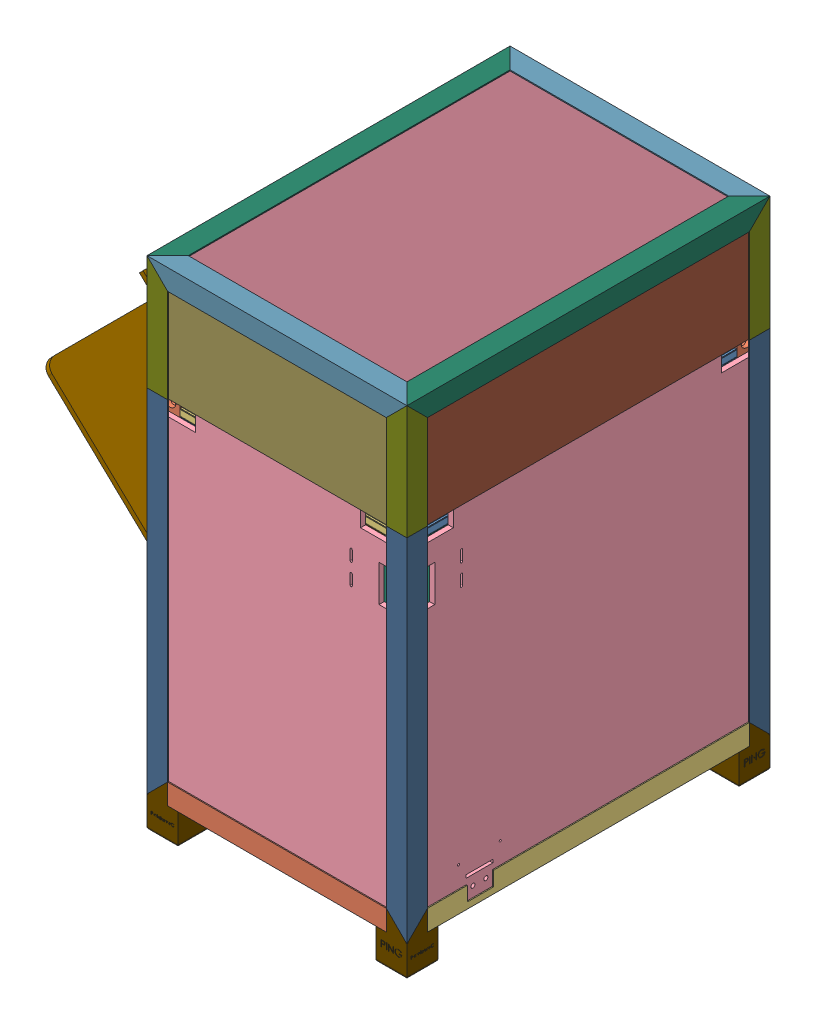
SolidWorks assembly carcasse, configuration Défaut. Lengths in mm.
Overall size (850.58 964 704).
62 component instances, 25 part files, 73 mates.
Components (placement in the parent):
- cadre-1: cadre [Défaut] at (-215.194 -19.8636 -400) size (480 40 680)
  - prof_40x40x600mm-1: prof_40x40x600mm [Défaut] at (-14.8937 4.0689 600) size (40 40 600)
  - Rexroth-Default-1: Rexroth-Default [Default] at (-14.8937 24.0689 720) x (0 -1 0) z (-1 0 0) size (40 40 40)
  - prof_40x40x600mm-3: prof_40x40x600mm [Défaut] at (425.1063 4.0689 600) size (40 40 600)
  - Rexroth-Default-3: Rexroth-Default [Default] at (-14.8937 24.0689 80) x (0 -1 0) z (0 0 -1) size (40 40 40)
  - Rexroth-Default-4: Rexroth-Default [Default] at (425.1063 24.0689 80) x (0 -1 0) z (1 0 0) size (40 40 40)
  - Rexroth-Default-5: Rexroth-Default [Default] at (425.1063 24.0689 720) x (0 -1 0) z (0 0 1) size (40 40 40)
  - prof_40x40x300mm-1: prof_40x40x300mm [Défaut] at (105.1063 4.0689 720) x (0 0 1) z (-1 0 0) size (40 40 400)
  - prof_40x40x300mm-2: prof_40x40x300mm [Défaut] at (105.1063 4.0689 80) x (0 0 1) z (-1 0 0) size (40 40 400)
- prof_40x40x600mm-1: prof_40x40x600mm [Défaut] at (209.9123 104.2053 -320) x (1 0 0) z (0 -1 0) size (40 40 600)
- prof_40x40x600mm-2: prof_40x40x600mm [Défaut] at (209.9123 104.2053 320) x (1 0 0) z (0 -1 0) size (40 40 600)
- prof_40x40x600mm-3: prof_40x40x600mm [Défaut] at (-230.0877 104.2053 320) x (1 0 0) z (0 -1 0) size (40 40 600)
- prof_40x40x600mm-4: prof_40x40x600mm [Défaut] at (-230.0877 104.2053 -320) x (1 0 0) z (0 -1 0) size (40 40 600)
- cadre-2: cadre [Défaut] at (195.0186 628.2742 -400) x (-1 0 0) z (0 0 1) size (480 40 680)
  - prof_40x40x600mm-1: prof_40x40x600mm [Défaut] at (-14.8937 4.0689 600) size (40 40 600)
  - Rexroth-Default-1: Rexroth-Default [Default] at (-14.8937 24.0689 720) x (0 -1 0) z (-1 0 0) size (40 40 40)
  - prof_40x40x600mm-3: prof_40x40x600mm [Défaut] at (425.1063 4.0689 600) size (40 40 600)
  - Rexroth-Default-3: Rexroth-Default [Default] at (-14.8937 24.0689 80) x (0 -1 0) z (0 0 -1) size (40 40 40)
  - Rexroth-Default-4: Rexroth-Default [Default] at (425.1063 24.0689 80) x (0 -1 0) z (1 0 0) size (40 40 40)
  - Rexroth-Default-5: Rexroth-Default [Default] at (425.1063 24.0689 720) x (0 -1 0) z (0 0 1) size (40 40 40)
  - prof_40x40x300mm-1: prof_40x40x300mm [Défaut] at (105.1063 4.0689 720) x (0 0 1) z (-1 0 0) size (40 40 400)
  - prof_40x40x300mm-2: prof_40x40x300mm [Défaut] at (105.1063 4.0689 80) x (0 0 1) z (-1 0 0) size (40 40 400)
- plaque_acrylique_680x670-2: plaque_acrylique_680x670 [Défaut] at (229.9123 299.2053 0) x (0 0 -1) z (1 0 0) size (680 670 10)
- plaque_acrylique_380x670_G-1: plaque_acrylique_380x670_G [Défaut] at (39.9123 299.2053 -350) size (480 670 10)
- plaque_acrylique_680x670_porte-1: plaque_acrylique_680x670_porte [Défaut] at (-260.0877 299.2053 0) x (0 0 -1) z (1 0 0) size (680 670 10)
- charniere-1: charniere [Défaut] at (-253.7309 154.2053 256.2875) x (0 0 1) z (0 -1 0) size (40 29.08 53.23)
  - axe charnière-1: axe charnière [Défaut] at (-76.2875 9.8568 0) size (40 5 5)
  - batant charnière-1: batant charnière [Défaut] at (-76.2875 10.1991 -17.6196) size (40 7 33.5)
  - batant charnière-2: batant charnière [Défaut] at (-36.2875 -2.6626 12.4029) x (-1 0 0) z (0 0.723942 -0.689861) size (40 7 33.5)
- charniere-2: charniere [Défaut] at (-253.7309 154.2053 -143.7125) x (0 0 1) z (0 -1 0) size (40 29.08 53.23)
  - axe charnière-1: axe charnière [Défaut] at (-76.2875 9.8568 0) size (40 5 5)
  - batant charnière-1: batant charnière [Défaut] at (-76.2875 10.1991 -17.6196) size (40 7 33.5)
  - batant charnière-2: batant charnière [Défaut] at (-36.2875 -2.6626 12.4029) x (-1 0 0) z (0 0.723942 -0.689861) size (40 7 33.5)
- porte-1: porte [Défaut] at (-366.1448 256.769 0) x (0 0 -1) z (0.689861 0.723942 0) size (480 480 10)
- eclisse_40x40x670_bisote_x1-1: eclisse_40x40x670_bisote_x1 [Défaut] at (-242.0877 -47.7947 -331.8864) size (40 682 40)
- eclisse_40x40x670_bisote_x1-2: eclisse_40x40x670_bisote_x1 [Défaut] at (-241.9741 -47.7947 332) x (0 0 -1) z (1 0 0) size (40 682 40)
- eclisse_40x40x670_bisote_x1-3: eclisse_40x40x670_bisote_x1 [Défaut] at (221.9123 -47.7947 331.8864) x (-1 0 0) z (0 0 -1) size (40 682 40)
- eclisse_40x40x670_bisote_x1-4: eclisse_40x40x670_bisote_x1 [Défaut] at (221.7986 -47.7947 -332) x (0 0 1) z (-1 0 0) size (40 682 40)
- couvercle-1: couvercle [Défaut] at (227.4119 747.9268 345) size (504 222 704)
  - plaque_acrylique_680x210-2: plaque_acrylique_680x210 [Défaut] at (-487.4996 -8.7215 -345) x (0 0 -1) z (1 0 0) size (680 210 10)
  - plaque_acrylique_380x210-2: plaque_acrylique_380x210 [Défaut] at (-187.4996 -8.7215 -695) size (480 210 10)
  - plaque_acrylique_380x680-1: plaque_acrylique_380x680 [Défaut] at (-187.4996 96.2785 -345) x (1 0 0) z (0 1 0) size (480 680 10)
  - eclisse_40x40x404_bisote_x2-1: eclisse_40x40x404_bisote_x2 [Défaut] at (14.5004 88.1649 -677) x (0 0 1) z (0 -1 0) size (40 504 40)
  - eclisse_40x40x704_bisote_x2-1: eclisse_40x40x704_bisote_x2 [Défaut] at (-5.6132 88.2785 -697) x (0 -1 0) z (-1 0 0) size (40 704 40)
  - eclisse_40x40x404_bisote_x2-2: eclisse_40x40x404_bisote_x2 [Défaut] at (-489.4996 88.1649 -13) x (0 0 -1) z (0 -1 0) size (40 504 40)
  - eclisse_40x40x704_bisote_x2-2: eclisse_40x40x704_bisote_x2 [Défaut] at (-469.4996 88.1649 -697) x (1 0 0) z (0 -1 0) size (40 704 40)
  - eclisse_40x40x222_bisote_x1-1: eclisse_40x40x222_bisote_x1 [Défaut] at (-469.386 108.2785 -677) x (0 0 1) z (1 0 0) size (40 222 40)
  - eclisse_40x40x222_bisote_x1-2: eclisse_40x40x222_bisote_x1 [Défaut] at (-5.4996 108.2785 -676.8864) x (-1 0 0) z (0 0 1) size (40 222 40)
  - eclisse_40x40x222_bisote_x1-4: eclisse_40x40x222_bisote_x1 [Défaut] at (-469.4996 108.2785 -13.1136) x (1 0 0) z (0 0 -1) size (40 222 40)
  - plaque_acrylique_380x210_Moteur-1: plaque_acrylique_380x210_Moteur [Défaut] at (-187.4996 -8.7215 -5) size (480 210 10)
  - plaque_acrylique_680x210_moteur-1: plaque_acrylique_680x210_moteur [Défaut] at (2.5004 -8.7215 -345) x (0 0 -1) z (1 0 0) size (680 210 10)
  - eclisse_40x40x222_bisote_x1_Moteur-1: eclisse_40x40x222_bisote_x1_Moteur [Défaut] at (-5.6132 108.2785 -13) x (0 0 -1) z (-1 0 0) size (40 222 40)
- plaque_acrylique_bas_380x680-1: plaque_acrylique_bas_380x680 [Défaut] at (39.9123 -35.7947 0) x (1 0 0) z (0 -1 0) size (480 680 10)
- Pied-1: Pied [Défaut] at (181.9123 -47.7947 -292) x (-1 0 0) z (0 -1 0) size (60 60 100)
- Pied-2: Pied [Défaut] at (181.9123 -47.7947 292) x (0 0 -1) z (0 -1 0) size (60 60 100)
- Pied-3: Pied [Défaut] at (-202.0877 -47.7947 292) x (1 0 0) z (0 -1 0) size (60 60 100)
- Pied-4: Pied [Défaut] at (-202.0877 -47.7947 -292) x (0 0 1) z (0 -1 0) size (60 60 100)
- eclisse_bas_40x40x704-2: eclisse_bas_40x40x704 [Défaut] at (-242.0877 -27.681 312) x (1 0 0) z (0 1 0) size (40 624 40)
- eclisse_bas_40x40x404-1: eclisse_bas_40x40x404 [Défaut] at (-222.0877 -27.681 -332) x (0 0 1) z (0 1 0) size (40 424 40)
- eclisse_bas_40x40x404-2: eclisse_bas_40x40x404 [Défaut] at (201.9123 -27.681 332) x (0 0 -1) z (0 1 0) size (40 424 40)
- eclisse_bas_support_Z_40x40x704-1: eclisse_bas_support_Z_40x40x704 [Défaut] at (221.7986 -27.7947 312) x (0 1 0) z (-1 0 0) size (40 624 40)
- plaque_acrylique_380x670_D-2: plaque_acrylique_380x670_D [Défaut] at (-60.0877 299.2053 350) x (-1 0 0) z (0 0 -1) size (480 670 10)
Mates (geometry in assembly coordinates):
- Coïncidente1: coincident anti-aligned: plane of cadre-1/Rexroth-Default-3 through (-230.0877 4.2053 -320) normal (0 1 0); plane of prof_40x40x600mm-4 through (-213.0877 4.2053 -337) normal (0 -1 0)
- Coïncidente2: coincident anti-aligned: plane of cadre-1/Rexroth-Default-1 through (-230.0877 4.2053 320) normal (0 1 0); plane of prof_40x40x600mm-3 through (-213.0877 4.2053 303) normal (0 -1 0)
- Coïncidente3: coincident anti-aligned: plane of cadre-1/Rexroth-Default-5 through (209.9123 4.2053 320) normal (0 1 0); plane of prof_40x40x600mm-2 through (226.9123 4.2053 303) normal (0 -1 0)
- Coïncidente4: coincident anti-aligned: plane of cadre-1/Rexroth-Default-4 through (209.9123 4.2053 -320) normal (0 1 0); plane of prof_40x40x600mm-1 through (226.9123 4.2053 -337) normal (0 -1 0)
- Coïncidente5: coincident aligned: plane of cadre-1/Rexroth-Default-4 through (229.9123 -15.7947 -320) normal (1 0 0); plane of prof_40x40x600mm-1 through (229.9123 604.2053 -314) normal (1 0 0)
- Coïncidente6: coincident aligned: plane of cadre-1/Rexroth-Default-4 through (209.9123 -15.7947 -340) normal (0 0 -1); plane of prof_40x40x600mm-1 through (215.9123 604.2053 -340) normal (0 0 -1)
- Coïncidente7: coincident aligned: plane of cadre-1/Rexroth-Default-5 through (229.9123 -15.7947 320) normal (1 0 0); plane of prof_40x40x600mm-2 through (229.9123 604.2053 303) normal (1 0 0)
- Coïncidente8: coincident aligned: plane of cadre-1/Rexroth-Default-5 through (209.9123 -15.7947 340) normal (0 0 1); plane of prof_40x40x600mm-2 through (226.9123 604.2053 340) normal (0 0 1)
- Coïncidente9: coincident aligned: plane of cadre-1/Rexroth-Default-1 through (-230.0877 -15.7947 340) normal (0 0 1); plane of prof_40x40x600mm-3 through (-213.0877 604.2053 340) normal (0 0 1)
- Coïncidente10: coincident aligned: plane of cadre-1/Rexroth-Default-1 through (-250.0877 -15.7947 320) normal (-1 0 0); plane of prof_40x40x600mm-3 through (-250.0877 604.2053 337) normal (-1 0 0)
- Coïncidente11: coincident aligned: plane of cadre-1/Rexroth-Default-3 through (-250.0877 -15.7947 -320) normal (-1 0 0); plane of prof_40x40x600mm-4 through (-250.0877 604.2053 -303) normal (-1 0 0)
- Coïncidente12: coincident aligned: plane of cadre-1/Rexroth-Default-3 through (-230.0877 -15.7947 -340) normal (0 0 -1); plane of prof_40x40x600mm-4 through (-247.0877 604.2053 -340) normal (0 0 -1)
- Coïncidente13: coincident anti-aligned: plane of prof_40x40x600mm-1 through (226.9123 604.2053 -337) normal (0 1 0); plane of cadre-2/Rexroth-Default-3 through (209.9123 604.2053 -320) normal (0 -1 0)
- Coïncidente14: coincident aligned: plane of prof_40x40x600mm-3 through (-250.0877 604.2053 337) normal (-1 0 0); plane of cadre-2/Rexroth-Default-5 through (-250.0877 624.2053 320) normal (-1 0 0)
- Coïncidente15: coincident aligned: plane of prof_40x40x600mm-3 through (-236.0877 604.2053 340) normal (0 0 1); plane of cadre-2/Rexroth-Default-5 through (-230.0877 624.2053 340) normal (0 0 1)
- Coïncidente38: coincident anti-aligned: plane of cadre-2/prof_40x40x600mm-1 through (229.9123 630.2053 -300) normal (1 0 0); plane of plaque_acrylique_680x670-2 through (229.9123 299.2053 0) normal (-1 0 0)
- Coïncidente39: coincident aligned: plane of prof_40x40x600mm-2 through (226.9123 604.2053 340) normal (0 0 1); plane of plaque_acrylique_680x670-2 through (239.9123 634.2053 340) normal (0 0 1)
- Coïncidente40: coincident aligned: plane of cadre-1/prof_40x40x600mm-3 through (215.9123 -35.7947 -300) normal (0 -1 0); plane of plaque_acrylique_680x670-2 through (239.9123 -35.7947 340) normal (0 -1 0)
- Coïncidente44: coincident aligned: plane of cadre-1/prof_40x40x300mm-2 through (189.9123 -35.7947 -337) normal (0 -1 0); plane of plaque_acrylique_380x670_G-1 through (-250.0877 -35.7947 -340) normal (0 -1 0)
- Coïncidente45: coincident aligned: plane of cadre-2/Rexroth-Default-4 through (-250.0877 624.2053 -320) normal (-1 0 0); plane of plaque_acrylique_380x670_G-1 through (-250.0877 634.2053 -340) normal (-1 0 0)
- Coïncidente46: coincident anti-aligned: plane of prof_40x40x600mm-4 through (-247.0877 604.2053 -340) normal (0 0 -1); plane of plaque_acrylique_380x670_G-1 through (39.9123 299.2053 -340) normal (0 0 1)
- Coïncidente48: coincident aligned: plane of cadre-2/Rexroth-Default-5 through (-230.0877 624.2053 340) normal (0 0 1); plane of plaque_acrylique_680x670_porte-1 through (-250.0877 634.2053 340) normal (0 0 1)
- Coïncidente50: coincident anti-aligned: plane of plaque_acrylique_680x670_porte-1 through (-260.0877 299.2053 0) normal (-1 0 0); plane of charniere-1/batant charnière-1 through (-260.0877 114.2053 220) normal (1 0 0)
- Coïncidente51: coincident anti-aligned: plane of plaque_acrylique_680x670_porte-1 through (-260.0877 299.2053 0) normal (-1 0 0); plane of charniere-2/batant charnière-1 through (-260.0877 114.2053 -180) normal (1 0 0)
- Distance4: distance = 20 mm anti-aligned: plane of charniere-2/batant charnière-1 through (-263.5877 154.2053 -220) normal (0 0 -1); plane of plaque_acrylique_680x670_porte-1 through (-260.0877 574.2053 -240) normal (0 0 1)
- Coïncidente54: coincident aligned: line of plaque_acrylique_680x670_porte-1 through (-260.0877 154.2053 220) axis (0 0 -1); line of charniere-2/batant charnière-1 through (-260.0877 154.2053 -180) axis (0 0 -1)
- Distance5: distance = 20 mm anti-aligned: plane of plaque_acrylique_680x670_porte-1 through (-260.0877 574.2053 240) normal (0 0 -1); plane of charniere-1/batant charnière-1 through (-263.5877 154.2053 220) normal (0 0 1)
- Coïncidente57: coincident aligned: line of plaque_acrylique_680x670_porte-1 through (-260.0877 154.2053 220) axis (0 0 -1); line of charniere-1/batant charnière-1 through (-260.0877 154.2053 220) axis (0 0 -1)
- Coïncidente62: coincident anti-aligned: plane of charniere-1/batant charnière-2 through (-290.1309 184.3336 180) normal (0.689861 0.723942 0); plane of porte-1 through (-586.947 467.1766 30) normal (-0.689861 -0.723942 0)
- Coïncidente63: coincident anti-aligned: line of charniere-1/batant charnière-2 through (-261.1732 156.7391 200) axis (0 0 1); line of porte-1 through (-261.1732 156.7391 220) axis (0 0 -1)
- Coïncidente64: coincident anti-aligned: plane of plaque_acrylique_680x670_porte-1 through (-260.0877 574.2053 240) normal (0 0 -1); plane of porte-1 through (-558.3301 453.7202 240) normal (0 0 1)
- Coïncidente65: coincident anti-aligned: plane of plaque_acrylique_380x670_G-1 through (39.9123 299.2053 -350) normal (0 0 -1); plane of eclisse_40x40x670_bisote_x1-1 through (-260.0877 634.2053 -350) normal (0 0 1)
- Coïncidente66: coincident anti-aligned: plane of plaque_acrylique_680x670_porte-1 through (-260.0877 299.2053 0) normal (-1 0 0); plane of eclisse_40x40x670_bisote_x1-1 through (-260.0877 634.2053 -350) normal (1 0 0)
- Coïncidente67: coincident aligned: plane of plaque_acrylique_680x670_porte-1 through (-250.0877 634.2053 340) normal (0 1 0); plane of eclisse_40x40x670_bisote_x1-1 through (-242.0877 634.2053 -331.8864) normal (0 1 0)
- Coïncidente68: coincident anti-aligned: plane of plaque_acrylique_680x670-2 through (239.9123 299.2053 0) normal (1 0 0); plane of eclisse_40x40x670_bisote_x1-4 through (239.9123 634.2053 -350) normal (-1 0 0)
- Coïncidente69: coincident anti-aligned: plane of plaque_acrylique_380x670_G-1 through (39.9123 299.2053 -350) normal (0 0 -1); plane of eclisse_40x40x670_bisote_x1-4 through (239.9123 634.2053 -350) normal (0 0 1)
- Coïncidente70: coincident aligned: plane of plaque_acrylique_380x670_G-1 through (-250.0877 634.2053 -340) normal (0 1 0); plane of eclisse_40x40x670_bisote_x1-4 through (221.7986 634.2053 -332) normal (0 1 0)
- Coïncidente72: coincident anti-aligned: plane of plaque_acrylique_680x670_porte-1 through (-260.0877 299.2053 0) normal (-1 0 0); plane of eclisse_40x40x670_bisote_x1-2 through (-260.0877 634.2053 350) normal (1 0 0)
- Coïncidente74: coincident anti-aligned: plane of plaque_acrylique_680x670-2 through (239.9123 299.2053 0) normal (1 0 0); plane of eclisse_40x40x670_bisote_x1-3 through (239.9123 634.2053 350) normal (-1 0 0)
- Coïncidente100: coincident: plane of plaque_acrylique_680x670_porte-1 through (-250.0877 634.2053 340) normal (0 1 0); line of eclisse_40x40x670_bisote_x1-2 through (-260.0877 634.2053 350) axis (0 0 -1)
- Coïncidente101: coincident anti-aligned: plane of prof_40x40x600mm-4 through (-250.0877 604.2053 -326) normal (-1 0 0); plane of plaque_acrylique_680x670_porte-1 through (-250.0877 299.2053 0) normal (1 0 0)
- Coïncidente116: coincident anti-aligned: line of plaque_acrylique_680x670-2 through (239.9123 634.2053 -260) axis (0 0 1); line of couvercle-1/plaque_acrylique_680x210_moteur-1 through (239.9123 634.2053 340) axis (0 0 -1)
- Coïncidente117: coincident anti-aligned: line of plaque_acrylique_380x670_G-1 through (149.9123 634.2053 -350) axis (-1 0 0); line of couvercle-1/plaque_acrylique_380x210-2 through (-170.0877 634.2053 -350) axis (1 0 0)
- Coïncidente118: coincident anti-aligned: plane of cadre-1/prof_40x40x600mm-1 through (-247.0877 -35.7947 -300) normal (0 -1 0); plane of plaque_acrylique_bas_380x680-1 through (39.9123 -35.7947 0) normal (0 1 0)
- Coïncidente119: coincident: plane of cadre-1/prof_40x40x600mm-1 through (-250.0877 -21.7947 -300) normal (-1 0 0); line of plaque_acrylique_bas_380x680-1 through (-250.0877 -35.7947 340) axis (0 0 -1)
- Coïncidente120: coincident: line of cadre-1/prof_40x40x300mm-2 through (189.9123 -32.7947 -340) axis (-1 0 0); plane of plaque_acrylique_bas_380x680-1 through (-250.0877 -45.7947 -340) normal (0 0 -1)
- Coaxiale1: concentric aligned: cylinder of plaque_acrylique_bas_380x680-1 through (209.9123 -35.7947 -320) axis (0 -1 0) radius 12.5; cylinder of Pied-1 through (209.9123 -27.7947 -320) axis (0 -1 0) radius 12
- Coïncidente124: coincident anti-aligned: plane of eclisse_40x40x670_bisote_x1-4 through (-348.0877 -47.7947 -352) normal (0 -0.707107 0.707107); plane of Pied-1 through (239.9123 -7.7947 -312) normal (0 0.707107 -0.707107)
- Coaxiale2: concentric aligned: circle of plaque_acrylique_bas_380x680-1; cylinder of Pied-2 through (209.9123 -27.7947 320) axis (0 -1 0) radius 12
- Coïncidente126: coincident anti-aligned: plane of eclisse_40x40x670_bisote_x1-3 through (241.9123 -47.7947 -238) normal (-0.707107 -0.707107 0); plane of Pied-2 through (201.9123 -7.7947 350) normal (0.707107 0.707107 0)
- Coaxiale3: concentric aligned: circle of plaque_acrylique_bas_380x680-1; cylinder of Pied-3 through (-230.0877 -27.7947 320) axis (0 -1 0) radius 12
- Coïncidente130: coincident anti-aligned: plane of eclisse_40x40x670_bisote_x1-2 through (327.9123 -47.7947 352) normal (0 -0.707107 -0.707107); plane of Pied-3 through (-260.0877 -7.7947 312) normal (0 0.707107 0.707107)
- Coaxiale4: concentric aligned: circle of plaque_acrylique_bas_380x680-1; cylinder of Pied-4 through (-230.0877 -27.7947 -320) axis (0 -1 0) radius 12
- Coïncidente131: coincident anti-aligned: plane of eclisse_40x40x670_bisote_x1-1 through (-262.0877 -47.7947 238) normal (0.707107 -0.707107 0); plane of Pied-4 through (-222.0877 -7.7947 -350) normal (-0.707107 0.707107 0)
- Coïncidente132: coincident anti-aligned: plane of plaque_acrylique_680x670_porte-1 through (-260.0877 299.2053 0) normal (-1 0 0); plane of eclisse_bas_40x40x704-2 through (-260.0877 -45.7947 -312) normal (1 0 0)
- Coïncidente133: coincident anti-aligned: plane of plaque_acrylique_bas_380x680-1 through (39.9123 -45.7947 0) normal (0 -1 0); plane of eclisse_bas_40x40x704-2 through (-260.0877 -45.7947 -312) normal (0 1 0)
- Coïncidente134: coincident anti-aligned: line of eclisse_40x40x670_bisote_x1-2 through (-262.0877 634.2053 312) axis (0 -1 0); line of eclisse_bas_40x40x704-2 through (-262.0877 -47.7947 312) axis (0 1 0)
- Coïncidente135: coincident anti-aligned: plane of plaque_acrylique_380x670_G-1 through (39.9123 299.2053 -350) normal (0 0 -1); plane of eclisse_bas_40x40x404-1 through (201.9123 -45.7947 -350) normal (0 0 1)
- Coïncidente136: coincident anti-aligned: plane of plaque_acrylique_bas_380x680-1 through (39.9123 -45.7947 0) normal (0 -1 0); plane of eclisse_bas_40x40x404-1 through (201.9123 -45.7947 -350) normal (0 1 0)
- Coïncidente137: coincident anti-aligned: line of Pied-1 through (201.9123 -7.7947 -352) axis (0 -1 0); line of eclisse_bas_40x40x404-1 through (201.9123 -47.7947 -352) axis (0 1 0)
- Coïncidente139: coincident anti-aligned: plane of plaque_acrylique_bas_380x680-1 through (39.9123 -45.7947 0) normal (0 -1 0); plane of eclisse_bas_40x40x404-2 through (-222.0877 -45.7947 350) normal (0 1 0)
- Coïncidente140: coincident anti-aligned: line of Pied-3 through (-222.0877 -7.7947 352) axis (0 -1 0); line of eclisse_bas_40x40x404-2 through (-222.0877 -47.7947 352) axis (0 1 0)
- Coïncidente142: coincident anti-aligned: plane of plaque_acrylique_680x670-2 through (239.9123 299.2053 0) normal (1 0 0); plane of eclisse_bas_support_Z_40x40x704-1 through (239.9123 -45.7947 -312) normal (-1 0 0)
- Coïncidente143: coincident anti-aligned: plane of plaque_acrylique_bas_380x680-1 through (39.9123 -45.7947 0) normal (0 -1 0); plane of eclisse_bas_support_Z_40x40x704-1 through (239.9123 -45.7947 -312) normal (0 1 0)
- Coïncidente144: coincident anti-aligned: plane of Pied-2 through (239.9123 -7.7947 312) normal (0 0 -1); plane of eclisse_bas_support_Z_40x40x704-1 through (221.7986 -27.7947 312) normal (0 0 1)
- Coïncidente151: coincident anti-aligned: plane of Pied-3 through (-202.0877 -47.7947 292) normal (0 1 0); plane of eclisse_bas_40x40x404-2 through (-222.0877 -47.7947 352) normal (0 -1 0)
- Coïncidente152: coincident anti-aligned: plane of Pied-2 through (181.9123 -47.7947 292) normal (0 1 0); plane of eclisse_bas_40x40x404-2 through (-222.0877 -47.7947 352) normal (0 -1 0)
- Coïncidente153: coincident anti-aligned: plane of cadre-2/Rexroth-Default-1 through (209.9123 624.2053 340) normal (0 0 1); plane of plaque_acrylique_380x670_D-2 through (-60.0877 299.2053 340) normal (0 0 -1)
- Coïncidente154: coincident aligned: plane of prof_40x40x600mm-3 through (-250.0877 604.2053 314) normal (-1 0 0); plane of plaque_acrylique_380x670_D-2 through (-250.0877 634.2053 340) normal (-1 0 0)
- Coïncidente155: coincident aligned: plane of cadre-1/prof_40x40x300mm-1 through (189.9123 -35.7947 303) normal (0 -1 0); plane of plaque_acrylique_380x670_D-2 through (229.9123 -35.7947 340) normal (0 -1 0)
- Coïncidente156: coincident anti-aligned: plane of eclisse_bas_40x40x404-2 through (-222.0877 -45.7947 350) normal (0 0 -1); plane of plaque_acrylique_380x670_D-2 through (-60.0877 299.2053 350) normal (0 0 1)
- Coïncidente157: coincident anti-aligned: plane of eclisse_40x40x670_bisote_x1-2 through (-260.0877 634.2053 350) normal (0 0 -1); plane of plaque_acrylique_380x670_D-2 through (-60.0877 299.2053 350) normal (0 0 1)
- Coïncidente158: coincident anti-aligned: plane of eclisse_40x40x670_bisote_x1-3 through (239.9123 634.2053 350) normal (0 0 -1); plane of plaque_acrylique_380x670_D-2 through (-60.0877 299.2053 350) normal (0 0 1)
